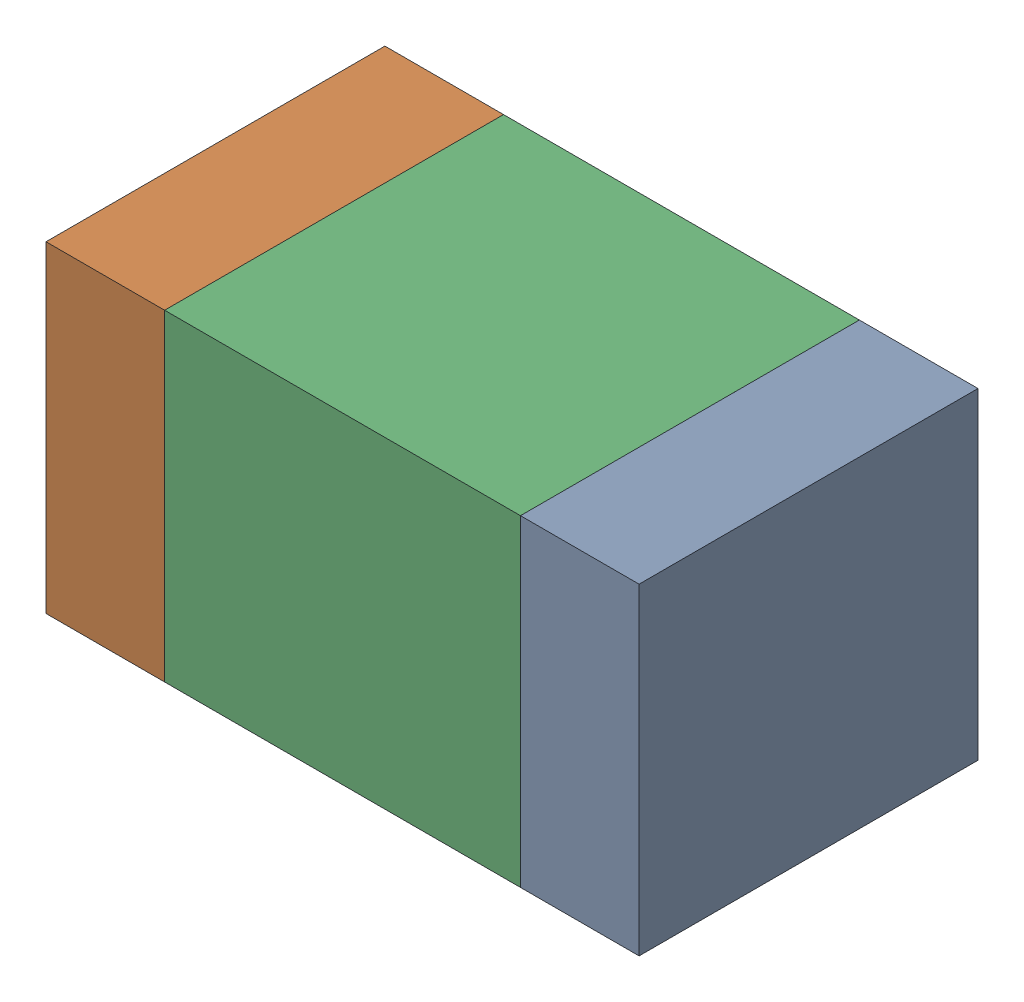
SolidWorks assembly C12-1, configuration Default. Lengths in mm.
Overall size (1.75 0.95 1).
6 component instances, 2 part files, 0 mates.
Components (placement in the parent):
- 959208936-1-1: 959208936-1 [Default] at (92.521 76.327 0) size (0.35 0.95 1)
  - Extruded-47-1: Extruded-47 [Default] at origin size (0.35 0.95 1)
- 959208936-1-2: 959208936-1 [Default] at (91.121 76.327 0) size (0.35 0.95 1)
  - Extruded-47-1: Extruded-47 [Default] at origin size (0.35 0.95 1)
- 959208800-1-1: 959208800-1 [Default] at (91.821 76.327 0) size (1.05 0.95 1)
  - Extruded-48-1: Extruded-48 [Default] at origin size (1.05 0.95 1)
